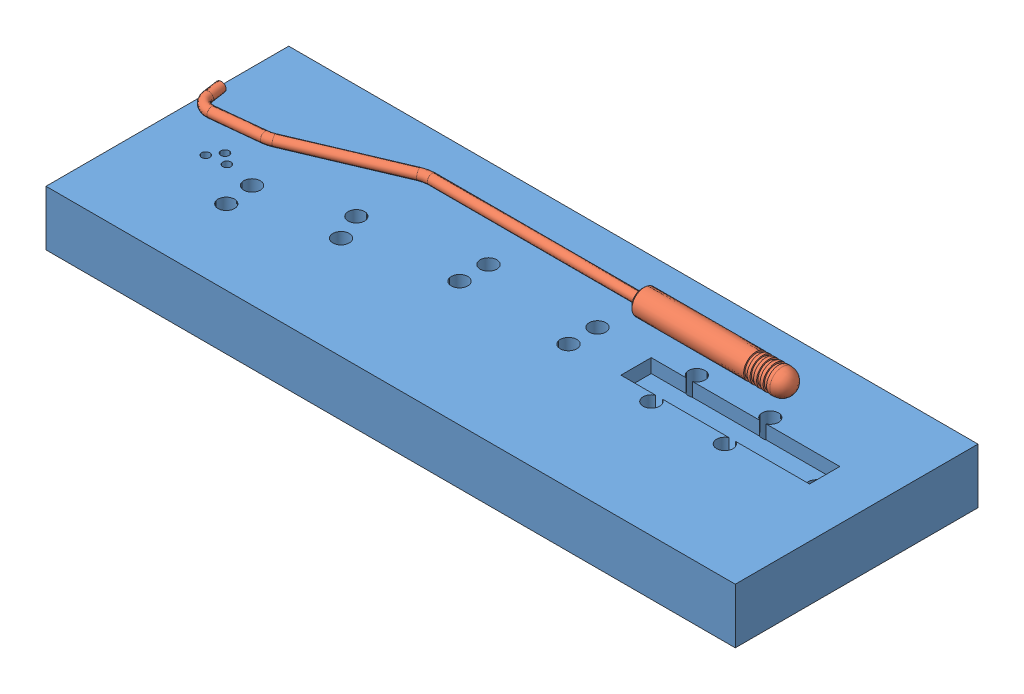
SolidWorks assembly Short Fixture, configuration Default. Lengths in mm.
Overall size (250 46.37 88.03).
2 component instances, 2 part files, 0 mates.
Components (placement in the parent):
- Saina_Short Fixture-1: Saina_Short Fixture [Default] at (95.1498 19.2583 -11.4137) x (1 0 0) z (0 1 0) size (250 88.03 20)
- Part1-1: Part1 [Default] at (33.0726 41.1332 -3.8077) x (1 0 0) z (0 0 -1) size (200.52 9 25.27)
